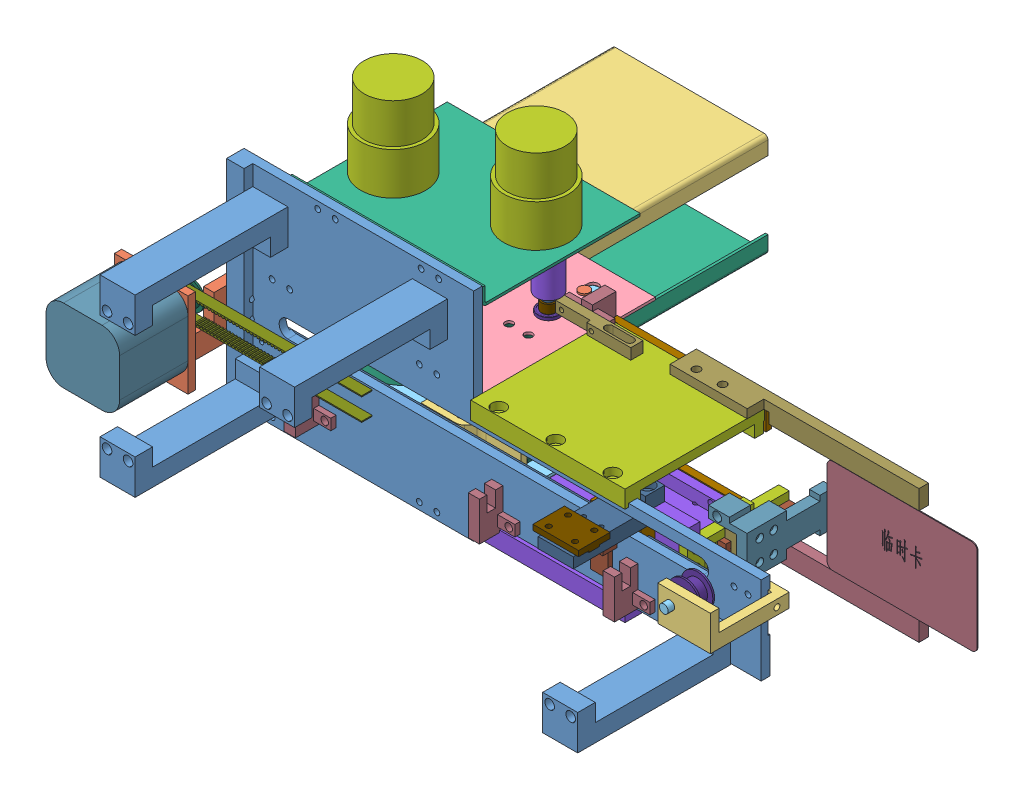
SolidWorks assembly 存储卡, configuration 默认. Lengths in mm.
Overall size (373.35 177.6 304.15).
71 component instances, 51 part files, 165 mates.
Components (placement in the parent):
- C017-1: C017 [默认] at (-172.2765 -67.8832 295) size (300 123.7 10)
- C003-1: C003 [默认] at (-172.9765 -8.6832 223) size (86 56 10)
- C004-1: C004 [默认] at (-85.4265 45.8168 83) x (-1 0 0) z (0 0 1) size (89.1 18.5 152)
- C005-2: C005 [默认] at (-37.6765 45.8168 295) x (0 -1 0) z (-1 0 0) size (10 100 134.6)
- 镜向C005-3: 镜向C005 [默认] at (-37.6765 -10.1832 295) x (0 1 0) z (1 0 0) size (10 100 134.6)
- C001-2: C001 [默认] at (-174.5265 -10.1832 83) size (89.1 33.5 152)
- C006-1-1: C006-1 [默认] at (68.7235 9.8168 231) x (0 1 0) z (1 0 0) size (24 57 6)
- C006-2-1: C006-2 [默认] at (73.7235 35.0668 291) x (0 -1 0) z (0 0 -1) size (34.5 50 13)
- MGN9C滑块-1: MGN9C滑块 [默认] at (24.2735 27.8168 286) x (0 -1 0) z (0 0 1) size (20 28.9 8)
- MGN9C线轨-265-1: MGN9C线轨-265 [默认] at (100.2235 13.3168 289.5) x (0 1 0) z (0 0 1) size (9 265 6.5)
- MGN7C线轨-40-1: MGN7C线轨-40 [默认] at (73.7235 14.3168 231) x (0 1 0) z (1 0 0) size (7 40 4.8)
- MGN7C滑块-1: MGN7C滑块 [默认] at (81.7235 9.3168 245.55) x (0 0 1) z (-1 0 0) size (22.5 17 6.5)
- 临时身份证卡片-1: 临时身份证卡片 [默认] at (88.3058 -9.1832 222.5) size (85.6 54 0.5)
- C007-1: C007 [默认] at (87.7235 17.8168 268.1) x (1 0 0) z (0 0 -1) size (22 30 49.6)
- C011-1: C011 [默认] at (-60.6765 -8.3832 224.8336) x (0 0 -1) z (0 -1 0) size (31.07 22 1.8)
- C012-1: C012 [默认] at (-60.6765 -9.3832 232.9) x (0.511883 0 -0.859055) z (0 1 0) size (8 8 1.2)
- MFL126ZZ-1: MFL126ZZ [默认] at (-60.6765 -13.3832 232.9) x (0 1 0) z (0.353832 0 -0.935309) size (23.7 35.7 35.7)
- C012-2: C012 [默认] at (-60.6765 45.0168 232.9) x (0.041323 0 -0.999146) z (0 -1 0) size (8 8 1.2)
- MFL126ZZ-2: MFL126ZZ [默认] at (-60.6765 49.0168 232.9) x (0 -1 0) z (-0.254645 0 -0.967035) size (23.7 35.7 35.7)
- C011-2: C011 [默认] at (-60.6765 44.0168 224.8336) x (0 0 -1) z (0 1 0) size (31.07 22 1.8)
- C015-1: C015 [默认] at (-60.6765 49.0168 232.9) x (-0.500335 0 -0.865832) z (0 1 0) size (8 8 5)
- C015-2: C015 [默认] at (-60.6765 -13.3832 232.9) x (0.575313 0 -0.817933) z (0 -1 0) size (8 8 5)
- 米思米止动扣环5-1: 米思米止动扣环5 [默认] at (-127.2765 -12.7832 247.9) x (-0.338524 0 -0.940958) z (0 1 0) size (11 8.93 0.6)
- MFL126ZZ-3: MFL126ZZ [默认] at (-127.2765 -8.4832 247.9) x (0 -1 0) z (0.834073 0 -0.551654) size (23.7 35.7 35.7)
- MFL126ZZ-4: MFL126ZZ [默认] at (-127.2765 44.1168 247.9) x (0 1 0) z (-0.070925 0 0.997482) size (23.7 35.7 35.7)
- 米思米止动扣环5-2: 米思米止动扣环5 [默认] at (-127.2765 48.4168 247.9) x (0.376434 0 -0.926444) z (0 1 0) size (11 8.93 0.6)
- C025-1: C025 [默认] at (-60.6765 45.3168 212.5) x (-0.469568 0 -0.882896) z (0 -1 0) size (8 8 61)
- C018-2: C018 [默认] at (-7934.5924 -10.1832 311.2708) x (1 0 0) z (0 1 0) size (50.64 10 10)
- 凸轮随动器-1: 凸轮随动器 [默认] at (84.7235 2.0168 265.1) x (0.072008 0 0.997404) z (0 -1 0) size (10 10 17.3)
- 米思米包胶滚轮ROUAKN20-8-15 -1: 米思米包胶滚轮ROUAKN20-8-15  [默认] at (-60.6765 43.8168 232.9) x (0.516691 0 -0.856172) z (0 -1 0) size (20 20 15)
- 米思米包胶滚轮ROUAKN20-8-15 -2: 米思米包胶滚轮ROUAKN20-8-15  [默认] at (-60.6765 28.8168 212.5) x (0.550183 0 0.835044) z (0 1 0) size (20 20 15)
- 米思米包胶滚轮ROUAKN20-8-15 -3: 米思米包胶滚轮ROUAKN20-8-15  [默认] at (-60.6765 6.8168 232.9) x (0.772118 0 -0.63548) z (0 -1 0) size (20 20 15)
- 米思米包胶滚轮ROUAKN20-8-15 -4: 米思米包胶滚轮ROUAKN20-8-15  [默认] at (-60.6765 -8.1832 212.5) x (0.999916 0 -0.01299) z (0 1 0) size (20 20 15)
- 米思米包胶滚轮ROUAKN50-12-30-1: 米思米包胶滚轮ROUAKN50-12-30 [默认] at (-127.2765 32.9168 247.9) x (0.950916 0 0.309448) z (0 -1 0) size (50 50 30)
- C019-1: C019 [默认] at (-35.9765 50.8168 302) x (0 0 1) z (1 0 0) size (79.6 12 88)
- 镜向C019-2: 镜向C019 [默认] at (-35.9765 -15.1832 302) x (0 0 1) z (-1 0 0) size (79.6 12 88)
- C020-1: C020 [默认] at (52.0235 38.8168 218.4) x (0 -1 0) z (0 0 1) size (12 88 4)
- C020-2: C020 [默认] at (-35.9765 -3.1832 218.4) x (0 1 0) z (0 0 1) size (12 88 4)
- C022-1: C022 [默认] at (53.7235 34.0668 281.04) x (0 -1 0) z (-1 0 0) size (15.25 52.16 20)
- C024-1: C024 [默认] at (53.7235 25.8168 308.3) x (-1 0 0) z (0 1 0) size (20 10.5 20)
- C026-1: C026 [默认] at (-54.9765 50.8168 234.7) x (1 0 0) z (0 1 0) size (45 7 6.2)
- EE-SX672遮光感应器-1: EE-SX672遮光感应器 [默认] at (-45.1765 60.2168 216.3) x (0 0 1) z (1 0 0) size (13.4 22.2 26)
- EE-SX672遮光感应器-2: EE-SX672遮光感应器 [默认] at (-130.9765 -6.4832 313.4) x (0 0 -1) z (1 0 0) size (13.4 22.2 26)
- EE-SX672遮光感应器-3: EE-SX672遮光感应器 [默认] at (-25.9765 -6.4832 313.4) x (0 0 -1) z (1 0 0) size (13.4 22.2 26)
- EE-SX672遮光感应器-4: EE-SX672遮光感应器 [默认] at (51.0235 -6.4832 313.4) x (0 0 -1) z (1 0 0) size (13.4 22.2 26)
- 42微型步进电机-1: 42微型步进电机 [默认] at (-199.4465 19.4168 380.8) x (0 1 0) z (0 0 -1) size (42 42 64)
- S2带轮-1: S2带轮 [默认] at (-178.4465 40.4168 318.8) x (-0.999895 -0.014472 0) z (0 0 1) size (16 16 16)
- S2M同步带-1: S2M同步带 [默认] at (-72.9684 34.4168 327.2) x (0 0 -1) z (-1 0 0) size (6 13.2 112.08)
- S2惰轮-1: S2惰轮 [默认] at (111.8256 40.4168 319.7) x (-0.381526 0.924358 0) z (0 0 1) size (18 18 8.5)
- S2M金属件-1: S2M金属件 [默认] at (30.7235 38.4168 315.2) x (1 0 0) z (0 -1 0) size (26 18 4)
- C023-4: C023 [默认] at (110.2235 -7.8832 300) x (0 -1 0) z (-1 0 0) size (20 87.15 20)
- C027-1: C027 [默认] at (-172.2765 40.8168 295.9995) x (0 -1 0) z (-1 0 0) size (48.6 50.8 42)
- C028-1: C028 [默认] at (124.7235 35.8168 311) x (0 -1 0) z (1 0 0) size (20 45 30)
- C029-1: C029 [默认] at (111.8256 40.4168 328.2) x (0.638272 -0.769811 0) z (0 0 1) size (7 7 2.8)
- 轴承止动销-1: 轴承止动销 [默认] at (111.8256 40.4168 317.7) x (0.999959 0.009096 0) z (0 0 1) size (8 8 22)
- C016-2: C016 [默认] at (-36.2765 92.9168 295) x (0 1 0) z (-1 0 0) size (10 90 110.1)
- 金顺来JGB37-520电机-12-66-3: 金顺来JGB37-520电机-12-66 [默认] at (-127.2765 94.4168 254.9) x (1 0 0) z (0 1 0) size (37 37 68.2)
- 金顺来JGB37-520电机-12-66-4: 金顺来JGB37-520电机-12-66 [默认] at (-60.6765 94.4168 239.9) x (1 0 0) z (0 1 0) size (37 37 68.2)
- LM-14联轴器-3: LM-14联轴器 [默认] at (-60.6765 79.9168 232.9) x (-0.273099 0 -0.961986) z (0 -1 0) size (14 14 22)
- LM-14联轴器-4: LM-14联轴器 [默认] at (-127.2765 79.9168 247.9) x (0.762245 0 -0.647289) z (0 -1 0) size (14 14 22)
- C014-2: C014 [默认] at (-60.6765 -18.1832 232.9) x (0.10754 0 0.994201) z (0 1 0) size (9 9 26)
- C010-2: C010 [默认] at (-60.6765 63.8168 232.9) x (0.999999 0 0.001231) z (0 -1 0) size (9 9 36)
- C009-3: C009 [默认] at (-127.2765 2.9168 247.9) x (0.688202 0 0.725519) z (0 1 0) size (12 12 80)
- C023-6: C023 [默认] at (-142.2765 -7.8832 300) x (0 -1 0) z (-1 0 0) size (20 87.15 20)
- C023-10: C023 [默认] at (-162.2765 92.1168 300) x (0 1 0) z (1 0 0) size (20 87.15 20)
- C023-11: C023 [默认] at (-71.2765 92.1168 300) x (0 1 0) z (1 0 0) size (20 87.15 20)
- C030-1: C030 [默认] at (8.1653 55.8168 222.4) x (1 0 0) z (0 -1 0) size (132.46 15 10.95)
- 镜向C030-2: 镜向C030 [默认] at (8.1653 -20.1832 222.4) x (1 0 0) z (0 -1 0) size (132.46 15 10.95)
- EE-SX672遮光感应器-5: EE-SX672遮光感应器 [默认] at (-140.8265 -36.4832 197.2) x (-1 0 0) z (0 0 -1) size (13.4 22.2 26)
- 弹簧1-1: 弹簧1 [默认] at (-145.1696 -18.7662 204.6463) x (-0.417818 -0.908531 0) z (0.908531 -0.417818 0) size (22.1 22.42 1.18)
- C031-1: C031 [默认] at (-147.0265 -0.6832 202) x (0 0 -1) z (-1 0 0) size (17 16 2)
Mates (geometry in assembly coordinates):
- 重合1: coincident aligned: plane of C017-1 through (-172.2765 -67.8832 305) normal (-1 0 0); plane of C005-2 through (-172.2765 55.8168 295) normal (-1 0 0)
- 重合3: coincident anti-aligned: plane of C017-1 through (-172.2765 -67.8832 295) normal (0 0 -1); plane of C005-2 through (-37.6765 45.8168 295) normal (0 0 1)
- 同心1: concentric anti-aligned: cylinder of C004-1 through (-165.9765 51.8168 225) axis (0 0 1) radius 2.25; cylinder of C005-2 through (-165.9765 51.8168 245) axis (0 0 -1) radius 2.25
- 同心2: concentric anti-aligned: cylinder of C004-1 through (-93.9765 51.8168 225) axis (0 0 1) radius 2.25; cylinder of C005-2 through (-93.9765 51.8168 245) axis (0 0 -1) radius 2.25
- 重合4: coincident anti-aligned: plane of C004-1 through (-85.4265 45.8168 235) normal (0 0 1); plane of C005-2 through (-37.6765 45.8168 235) normal (0 0 -1)
- 同心3: concentric anti-aligned: cylinder of 镜向C005-3 through (-165.9765 -16.1832 245) axis (0 0 -1) radius 2.25; cylinder of C001-2 through (-165.9765 -16.1832 225) axis (0 0 1) radius 2.25
- 同心4: concentric anti-aligned: cylinder of 镜向C005-3 through (-93.9765 -16.1832 245) axis (0 0 -1) radius 2.25; cylinder of C001-2 through (-93.9765 -16.1832 225) axis (0 0 1) radius 2.25
- 重合5: coincident anti-aligned: plane of 镜向C005-3 through (-37.6765 -10.1832 235) normal (0 0 -1); plane of C001-2 through (-174.5265 -10.1832 235) normal (0 0 1)
- 同心5: concentric aligned: circle of C003-1; cylinder of C004-1 through (-102.4765 37.3168 228.5) axis (0 1 0) radius 2.25
- 同心6: concentric aligned: cylinder of C003-1 through (-157.4765 -10.1832 228.5) axis (0 1 0) radius 2.0729; cylinder of C004-1 through (-157.4765 37.3168 228.5) axis (0 1 0) radius 2.25
- 重合6: coincident anti-aligned: plane of C003-1 through (-172.9765 45.8168 223) normal (0 1 0); plane of C004-1 through (-85.4265 45.8168 235) normal (0 -1 0)
- 同心9: concentric aligned: cylinder of C006-1-1 through (68.7235 22.5668 283) axis (1 0 0) radius 2.25; cylinder of C006-2-1 through (68.7235 22.5668 283) axis (1 0 0) radius 1.65
- 同心10: concentric aligned: cylinder of C006-1-1 through (68.7235 13.0668 283) axis (1 0 0) radius 2.25; cylinder of C006-2-1 through (68.7235 13.0668 283) axis (1 0 0) radius 1.65
- 重合8: coincident anti-aligned: plane of C006-1-1 through (68.7235 9.8168 231) normal (-1 0 0); plane of C006-2-1 through (68.7235 25.8168 291) normal (1 0 0)
- 同心11: concentric anti-aligned: cylinder of C017-1 through (-157.2765 17.8168 300) axis (0 0 1) radius 1.25; cylinder of MGN9C线轨-265-1 through (-157.2765 17.8168 289.5) axis (0 0 -1) radius 3.25
- 同心12: concentric anti-aligned: cylinder of C017-1 through (92.7235 17.8168 300) axis (0 0 1) radius 1.25; cylinder of MGN9C线轨-265-1 through (92.7235 17.8168 289.5) axis (0 0 -1) radius 3.25
- 重合9: coincident anti-aligned: plane of C017-1 through (-172.2765 22.3168 296) normal (0 0 -1); plane of MGN9C线轨-265-1 through (100.2235 13.3168 296) normal (0 0 1)
- 同心13: concentric aligned: cylinder of C006-2-1 through (33.7235 10.3168 281) axis (0 0 -1) radius 3.25; cylinder of MGN9C滑块-1 through (33.7235 10.3168 286) axis (0 0 -1) radius 1.25
- 同心14: concentric aligned: cylinder of C006-2-1 through (33.7235 25.3168 281) axis (0 0 -1) radius 3.25; cylinder of MGN9C滑块-1 through (33.7235 25.3168 286) axis (0 0 -1) radius 1.25
- 重合10: coincident anti-aligned: plane of C006-2-1 through (73.7235 27.8168 286) normal (0 0 1); plane of MGN9C滑块-1 through (24.2735 27.8168 286) normal (0 0 -1)
- 重合11: coincident anti-aligned: plane of MGN9C滑块-1 through (24.2735 13.3168 294) normal (0 1 0); plane of MGN9C线轨-265-1 through (100.2235 13.3168 296) normal (0 -1 0)
- 重合12: coincident anti-aligned: plane of MGN9C滑块-1 through (24.2735 22.3168 289.5) normal (0 0 1); plane of MGN9C线轨-265-1 through (100.2235 13.3168 289.5) normal (0 0 -1)
- 同心15: concentric anti-aligned: cylinder of C006-1-1 through (68.7235 17.8168 236) axis (-1 0 0) radius 1.25; cylinder of MGN7C线轨-40-1 through (78.5235 17.8168 236) axis (1 0 0) radius 2.2
- 同心16: concentric anti-aligned: cylinder of C006-1-1 through (68.7235 17.8168 266) axis (-1 0 0) radius 1.25; circle of MGN7C线轨-40-1
- 重合13: coincident anti-aligned: plane of C006-1-1 through (73.7235 9.8168 231) normal (1 0 0); plane of MGN7C线轨-40-1 through (73.7235 14.3168 231) normal (-1 0 0)
- 重合14: coincident anti-aligned: plane of MGN7C线轨-40-1 through (78.5235 14.3168 231) normal (0 -1 0); plane of MGN7C滑块-1 through (75.2235 14.3168 268.05) normal (0 1 0)
- 重合15: coincident anti-aligned: plane of MGN7C线轨-40-1 through (78.5235 14.3168 231) normal (1 0 0); plane of MGN7C滑块-1 through (78.5235 14.3168 268.05) normal (-1 0 0)
- 对称1: symmetric aligned: plane of 临时身份证卡片-1 through (88.3058 44.8168 223) normal (0 1 0); plane of 临时身份证卡片-1 through (88.3058 -9.1832 223) normal (0 -1 0); plane of assembly through (0 17.8168 0) normal (0 -1 0)
- 重合16: coincident anti-aligned: plane of C003-1 through (-172.9765 -8.6832 223) normal (0 0 -1); plane of 临时身份证卡片-1 through (88.3058 -9.1832 223) normal (0 0 1)
- 同心17: concentric aligned: cylinder of MGN7C滑块-1 through (81.7235 23.8168 252.8) axis (1 0 0) radius 0.8; cylinder of C007-1 through (87.7235 23.8168 252.8) axis (1 0 0) radius 2.2
- 同心18: concentric aligned: cylinder of MGN7C滑块-1 through (81.7235 23.8168 260.8) axis (1 0 0) radius 0.8; cylinder of C007-1 through (87.7235 23.8168 260.8) axis (1 0 0) radius 2.2
- 重合17: coincident anti-aligned: plane of MGN7C滑块-1 through (81.7235 9.3168 245.55) normal (1 0 0); plane of C007-1 through (81.7235 9.3168 218.5) normal (-1 0 0)
- 同心24: concentric anti-aligned: cylinder of 镜向C005-3 through (-60.6765 -1.6832 232.9) axis (0 -1 0) radius 6; cylinder of MFL126ZZ-1 through (-60.6765 -13.2332 232.9) axis (0 1 0) radius 3
- 重合21: coincident anti-aligned: plane of 镜向C005-3 through (-172.2765 -10.1832 295) normal (0 1 0); plane of MFL126ZZ-1 through (-69.5479 -10.1832 236.9015) normal (0 -1 0)
- 重合22: coincident anti-aligned: plane of C011-1 through (-60.6765 -9.3832 232.9) normal (0 -1 0); plane of MFL126ZZ-1 through (-64.678 -9.3832 224.0286) normal (0 1 0)
- 平行1: parallel aligned: plane of 镜向C005-3 through (-37.6765 -10.1832 295) normal (1 0 0); plane of C011-1 through (-49.6765 -10.1832 232.9) normal (1 0 0)
- 重合24: coincident anti-aligned: plane of C012-1 through (-60.6765 -9.3832 232.9) normal (0 -1 0); plane of MFL126ZZ-1 through (-62.9509 -9.3832 227.8577) normal (0 1 0)
- 同心28: concentric aligned: cylinder of C005-2 through (-60.6765 37.3168 232.9) axis (0 1 0) radius 6; cylinder of C012-2 through (-60.6765 43.8168 232.9) axis (0 1 0) radius 4
- 重合27: coincident anti-aligned: plane of C005-2 through (-172.2765 45.8168 295) normal (0 -1 0); plane of MFL126ZZ-2 through (-52.2694 45.8168 237.8024) normal (0 1 0)
- 重合28: coincident anti-aligned: plane of C012-2 through (-60.6765 45.0168 232.9) normal (0 1 0); plane of MFL126ZZ-2 through (-57.8901 45.0168 228.1215) normal (0 -1 0)
- 重合29: coincident anti-aligned: plane of MFL126ZZ-2 through (-55.7741 45.0168 224.4929) normal (0 -1 0); plane of C011-2 through (-60.6765 45.0168 232.9) normal (0 1 0)
- 平行2: parallel aligned: plane of C005-2 through (-37.6765 45.8168 295) normal (1 0 0); plane of C011-2 through (-49.6765 45.8168 255.9) normal (1 0 0)
- 重合32: coincident anti-aligned: plane of MFL126ZZ-2 through (-55.8981 49.0168 235.6864) normal (0 1 0); plane of C015-1 through (-60.6765 49.0168 232.9) normal (0 -1 0)
- 重合33: coincident anti-aligned: plane of MFL126ZZ-1 through (-65.7188 -13.3832 235.1744) normal (0 -1 0); plane of C015-2 through (-60.6765 -13.3832 232.9) normal (0 1 0)
- 重合40: coincident anti-aligned: plane of 镜向C005-3 through (-172.2765 -11.6832 295) normal (0 -1 0); plane of MFL126ZZ-3 through (-129.22 -11.6832 257.436) normal (0 1 0)
- 重合42: coincident anti-aligned: plane of C005-2 through (-172.2765 47.3168 295) normal (0 1 0); plane of MFL126ZZ-4 through (-119.9242 47.3168 241.5238) normal (0 -1 0)
- 重合45: coincident anti-aligned: plane of 米思米止动扣环5-1 through (-122.1148 -12.4832 251.9583) normal (0 1 0); plane of MFL126ZZ-3 through (-121.8564 -12.4832 249.0046) normal (0 -1 0)
- 重合46: coincident anti-aligned: plane of MFL126ZZ-4 through (-123.6524 48.1168 252.0789) normal (0 1 0); plane of 米思米止动扣环5-2 through (-121.9544 48.1168 244.0546) normal (0 -1 0)
- 同心40: concentric anti-aligned: cylinder of C005-2 through (-60.6765 37.3168 212.5) axis (0 1 0) radius 3; cylinder of C025-1 through (-60.6765 48.3168 212.5) axis (0 -1 0) radius 3
- 对称3: symmetric aligned: plane of C025-1 through (-60.6765 -9.6832 212.5) normal (0 -1 0); plane of C025-1 through (-60.6765 45.3168 212.5) normal (0 1 0); plane of assembly through (0 17.8168 0) normal (0 -1 0)
- 同心43: concentric anti-aligned: cylinder of 镜向C005-3 through (-81.8765 -1.6832 261.6) axis (0 -1 0) radius 2.25; cylinder of C018-2 through (-81.8765 -0.1832 261.6) axis (0 1 0) radius 1.65
- 同心44: concentric anti-aligned: cylinder of 镜向C005-3 through (-93.8765 -1.6832 261.6) axis (0 -1 0) radius 2.25; cylinder of C018-2 through (-93.8765 -0.1832 261.6) axis (0 1 0) radius 1.65
- 重合48: coincident anti-aligned: plane of 镜向C005-3 through (-172.2765 -10.1832 295) normal (0 1 0); plane of C018-2 through (-7934.5924 -10.1832 311.2708) normal (0 -1 0)
- 同心45: concentric aligned: cylinder of C007-1 through (84.7235 5.8168 265.1) axis (0 -1 0) radius 1.25; cylinder of 凸轮随动器-1 through (84.7235 10.3168 265.1) axis (0 -1 0) radius 1.5
- 距离1: distance = 4.5 mm anti-aligned: plane of 凸轮随动器-1 through (84.7235 10.3168 265.1) normal (0 1 0); plane of C007-1 through (77.7235 5.8168 218.5) normal (0 -1 0)
- LimitDistance1: limit distance = 0 mm anti-aligned: plane of C007-1 through (65.7235 2.8168 256.1) normal (0 0 -1); plane of C006-1-1 through (74.7235 25.8168 256.1) normal (0 0 1)
- 同心47: concentric anti-aligned: cylinder of C025-1 through (-60.6765 -9.6832 212.5) axis (0 1 0) radius 4; cylinder of 米思米包胶滚轮ROUAKN20-8-15 -2 through (-60.6765 43.8168 212.5) axis (0 -1 0) radius 4
- 重合50: coincident aligned: plane of 米思米包胶滚轮ROUAKN20-8-15 -1 through (-60.6765 28.8168 232.9) normal (0 -1 0); plane of 米思米包胶滚轮ROUAKN20-8-15 -2 through (-60.6765 28.8168 212.5) normal (0 -1 0)
- 同心50: concentric anti-aligned: cylinder of C025-1 through (-60.6765 -9.6832 212.5) axis (0 1 0) radius 4; cylinder of 米思米包胶滚轮ROUAKN20-8-15 -4 through (-60.6765 6.8168 212.5) axis (0 -1 0) radius 4
- 重合53: coincident aligned: plane of 米思米包胶滚轮ROUAKN20-8-15 -3 through (-60.6765 6.8168 232.9) normal (0 1 0); plane of 米思米包胶滚轮ROUAKN20-8-15 -4 through (-60.6765 6.8168 212.5) normal (0 1 0)
- 同心52: concentric aligned: cylinder of C017-1 through (40.5235 42.8168 297.5) axis (0 1 0) radius 1.65; cylinder of C019-1 through (40.5235 50.8168 297.5) axis (0 1 0) radius 4
- 同心56: concentric aligned: cylinder of C017-1 through (8.0235 42.8168 297.5) axis (0 1 0) radius 1.65; cylinder of C019-1 through (8.0235 50.8168 297.5) axis (0 1 0) radius 4
- 重合55: coincident anti-aligned: plane of C017-1 through (-36.2765 42.8168 305) normal (0 1 0); plane of C019-1 through (52.0235 42.8168 295) normal (0 -1 0)
- 同心57: concentric aligned: cylinder of C019-1 through (40.5235 47.8168 222.4) axis (0 0 -1) radius 1.25; cylinder of C020-1 through (40.5235 47.8168 222.4) axis (0 0 -1) radius 1.75
- 同心58: concentric aligned: cylinder of C019-1 through (8.0235 47.8168 222.4) axis (0 0 -1) radius 1.25; cylinder of C020-1 through (8.0235 47.8168 222.4) axis (0 0 -1) radius 1.75
- 重合56: coincident anti-aligned: plane of C019-1 through (52.0235 50.8168 222.4) normal (0 0 -1); plane of C020-1 through (52.0235 38.8168 222.4) normal (0 0 1)
- 同心59: concentric aligned: cylinder of 镜向C019-2 through (40.5235 -12.1832 222.4) axis (0 0 -1) radius 1.25; cylinder of C020-2 through (40.5235 -12.1832 222.4) axis (0 0 -1) radius 1.75
- 同心60: concentric aligned: cylinder of 镜向C019-2 through (8.0235 -12.1832 222.4) axis (0 0 -1) radius 1.25; cylinder of C020-2 through (8.0235 -12.1832 222.4) axis (0 0 -1) radius 1.75
- 重合57: coincident anti-aligned: plane of 镜向C019-2 through (52.0235 -15.1832 222.4) normal (0 0 -1); plane of C020-2 through (-35.9765 -3.1832 222.4) normal (0 0 1)
- 同心61: concentric aligned: cylinder of C006-2-1 through (38.7235 34.0668 286) axis (0 1 0) radius 1.65; cylinder of C022-1 through (38.7235 43.0668 286) axis (0 1 0) radius 4
- 同心62: concentric aligned: cylinder of C006-2-1 through (48.7235 34.0668 286) axis (0 1 0) radius 1.65; cylinder of C022-1 through (48.7235 43.0668 286) axis (0 1 0) radius 4
- 重合58: coincident anti-aligned: plane of C006-2-1 through (73.7235 34.0668 291) normal (0 1 0); plane of C022-1 through (33.7235 34.0668 291.04) normal (0 -1 0)
- 同心63: concentric aligned: cylinder of C022-1 through (48.7235 27.8168 312.3) axis (0 -1 0) radius 1.25; cylinder of C024-1 through (48.7235 45.8168 312.3) axis (0 -1 0) radius 1.75
- 同心64: concentric aligned: cylinder of C022-1 through (38.7235 27.8168 312.3) axis (0 -1 0) radius 1.25; cylinder of C024-1 through (38.7235 45.8168 312.3) axis (0 -1 0) radius 1.75
- 重合59: coincident anti-aligned: plane of C022-1 through (33.7235 27.8168 291.04) normal (0 -1 0); plane of C024-1 through (53.7235 27.8168 308.3) normal (0 1 0)
- 同心67: concentric anti-aligned: cylinder of C017-1 through (95.2235 7.1168 295) axis (0 0 1) radius 2.25; cylinder of C023-4 through (95.2235 7.1168 300) axis (0 0 -1) radius 1.65
- 同心68: concentric anti-aligned: cylinder of C017-1 through (105.2235 7.1168 295) axis (0 0 1) radius 2.25; cylinder of C023-4 through (105.2235 7.1168 300) axis (0 0 -1) radius 1.65
- 重合61: coincident anti-aligned: plane of C017-1 through (-172.2765 -67.8832 300) normal (0 0 1); plane of C023-4 through (90.2235 12.1168 300) normal (0 0 -1)
- 重合62: coincident anti-aligned: plane of C019-1 through (52.0235 50.8168 302) normal (0 1 0); plane of C026-1 through (-54.9765 50.8168 234.7) normal (0 -1 0)
- 平行3: parallel aligned: plane of C005-2 through (-37.6765 45.8168 295) normal (1 0 0); plane of C026-1 through (-9.9765 57.0168 236.7) normal (1 0 0)
- 同心69: concentric anti-aligned: cylinder of C026-1 through (-32.4765 53.9168 236.7) axis (0 0 1) radius 1.25; cylinder of EE-SX672遮光感应器-1 through (-32.4765 53.9168 236.5) axis (0 0 -1) radius 2.15
- 同心70: concentric anti-aligned: cylinder of C026-1 through (-51.4765 53.9168 236.7) axis (0 0 1) radius 1.25; cylinder of EE-SX672遮光感应器-1 through (-51.4765 53.9168 236.5) axis (0 0 -1) radius 2.15
- 重合64: coincident anti-aligned: plane of C026-1 through (-9.9765 57.0168 229.7) normal (0 0 -1); plane of EE-SX672遮光感应器-1 through (-38.7765 60.2168 229.7) normal (0 0 1)
- 同心71: concentric anti-aligned: cylinder of C019-1 through (-13.9765 50.8168 233.2) axis (0 1 0) radius 1.65; cylinder of C026-1 through (-13.9765 57.0168 233.2) axis (0 -1 0) radius 2.25
- 同心72: concentric aligned: cylinder of C017-1 through (-118.2765 -0.1832 300) axis (0 0 1) radius 1.25; cylinder of EE-SX672遮光感应器-2 through (-118.2765 -0.1832 293.2) axis (0 0 1) radius 2.15
- 同心73: concentric aligned: cylinder of C017-1 through (-137.2765 -0.1832 300) axis (0 0 1) radius 1.25; cylinder of EE-SX672遮光感应器-2 through (-137.2765 -0.1832 293.2) axis (0 0 1) radius 2.15
- 重合65: coincident anti-aligned: plane of C017-1 through (-172.2765 -67.8832 300) normal (0 0 1); plane of EE-SX672遮光感应器-2 through (-124.5765 -6.4832 300) normal (0 0 -1)
- 同心81: concentric aligned: cylinder of C022-1 through (36.2235 27.8168 318.7) axis (0 -1 0) radius 1.25; cylinder of S2M金属件-1 through (36.2235 39.3168 318.7) axis (0 -1 0) radius 1.5
- 同心82: concentric aligned: cylinder of C022-1 through (36.2235 27.8168 329.7) axis (0 -1 0) radius 1.25; cylinder of S2M金属件-1 through (36.2235 39.3168 329.7) axis (0 -1 0) radius 1.5
- 重合72: coincident anti-aligned: plane of C022-1 through (33.7235 33.8168 315.2) normal (0 1 0); plane of S2M同步带-1 through (-172.9684 33.8168 327.2) normal (0 -1 0)
- 重合73: coincident aligned: plane of S2M同步带-1 through (-172.9684 34.4168 321.2) normal (0 0 -1); plane of S2M金属件-1 through (30.7235 34.4168 321.2) normal (0 0 -1)
- 重合74: coincident anti-aligned: plane of S2M同步带-1 through (-172.9684 34.4168 327.2) normal (0 1 0); plane of S2M金属件-1 through (30.7235 34.4168 315.2) normal (0 -1 0)
- 同心83: concentric anti-aligned: cylinder of 42微型步进电机-1 through (-178.4465 40.4168 316.8) axis (0 0 1) radius 2.5; cylinder of S2带轮-1 through (-178.4465 40.4168 334.8) axis (0 0 -1) radius 2.5
- 重合75: coincident anti-aligned: plane of S2带轮-1 through (-178.4465 40.4168 327.2) normal (0 0 -1); plane of S2M同步带-1 through (-172.9684 34.4168 327.2) normal (0 0 1)
- 同心85: concentric aligned: cylinder of S2带轮-1 through (-178.4465 40.4168 327.2) axis (0 0 -1) radius 6; cylinder of S2M同步带-1 through (-178.4465 40.4168 327.2) axis (0 0 -1) radius 6
- 距离3: distance = 2 mm aligned: plane of 42微型步进电机-1 through (-178.4465 40.4168 316.8) normal (0 0 -1); plane of S2带轮-1 through (-178.4465 40.4168 318.8) normal (0 0 -1)
- 平行8: parallel aligned: plane of C017-1 through (-172.2765 -67.8832 305) normal (-1 0 0); plane of 42微型步进电机-1 through (-199.4465 19.4168 341.8) normal (-1 0 0)
- 重合78: coincident aligned: plane of S2带轮-1 through (-178.4465 40.4168 327.2) normal (0 0 -1); plane of S2惰轮-1 through (111.8256 40.4168 327.2) normal (0 0 -1)
- 相切1: tangent anti-aligned: plane of S2M同步带-1 through (-172.9684 34.4168 327.2) normal (0 1 0); cylinder of S2惰轮-1 through (111.8256 40.4168 327.2) axis (0 0 -1) radius 6
- 同心86: concentric aligned: cylinder of C017-1 through (-172.2765 36.8168 300.304) axis (-1 0 0) radius 1.65; cylinder of C027-1 through (-172.2765 36.8168 300.304) axis (-1 0 0) radius 2.1
- 同心87: concentric aligned: cylinder of C017-1 through (-172.2765 26.8168 300.304) axis (-1 0 0) radius 1.65; cylinder of C027-1 through (-172.2765 26.8168 300.304) axis (-1 0 0) radius 2.1
- 重合79: coincident anti-aligned: plane of C017-1 through (-172.2765 -67.8832 305) normal (-1 0 0); plane of C027-1 through (-172.2765 40.8168 295.9995) normal (1 0 0)
- 重合80: coincident anti-aligned: plane of C017-1 through (-172.2765 35.8168 295) normal (0 -1 0); plane of C028-1 through (134.7235 35.8168 311) normal (0 1 0)
- 重合81: coincident anti-aligned: plane of C017-1 through (-172.2765 35.8168 296) normal (0 0 -1); plane of C028-1 through (129.7235 25.8168 296) normal (0 0 1)
- 同心88: concentric aligned: cylinder of C028-1 through (111.8256 40.4168 336) axis (0 0 -1) radius 2.5; cylinder of C029-1 through (111.8256 40.4168 331) axis (0 0 -1) radius 2.5
- 重合82: coincident anti-aligned: plane of S2惰轮-1 through (111.8256 40.4168 328.2) normal (0 0 1); plane of C029-1 through (111.8256 40.4168 328.2) normal (0 0 -1)
- 同心89: concentric anti-aligned: cylinder of S2惰轮-1 through (111.8256 40.4168 319.7) axis (0 0 1) radius 2.5; cylinder of C029-1 through (111.8256 40.4168 331) axis (0 0 -1) radius 2.5
- 距离4: distance = 2 mm anti-aligned: plane of C017-1 through (127.7235 -7.1832 305) normal (1 0 0); plane of C028-1 through (129.7235 25.8168 311) normal (-1 0 0)
- 重合84: coincident aligned: plane of 42微型步进电机-1 through (-199.4465 19.4168 341.8) normal (-1 0 0); plane of C027-1 through (-199.4465 12.8168 337.5995) normal (-1 0 0)
- LimitDistance2: limit distance = 206 mm aligned: plane of C017-1 through (-172.2765 -67.8832 305) normal (-1 0 0); plane of C022-1 through (33.7235 34.0668 281.04) normal (-1 0 0)
- 同心93: concentric anti-aligned: cylinder of S2惰轮-1 through (111.8256 40.4168 319.7) axis (0 0 1) radius 2.5; cylinder of 轴承止动销-1 through (111.8256 40.4168 339.7) axis (0 0 -1) radius 2.5
- 重合85: coincident anti-aligned: plane of S2惰轮-1 through (111.8256 40.4168 319.7) normal (0 0 -1); plane of 轴承止动销-1 through (111.8256 40.4168 319.7) normal (0 0 1)
- 平行13: parallel aligned: plane of C017-1 through (-172.2765 -67.8832 305) normal (-1 0 0); plane of C016-2 through (-146.3765 92.9168 295) normal (-1 0 0)
- 重合90: coincident anti-aligned: plane of C017-1 through (-172.2765 -67.8832 295) normal (0 0 -1); plane of C016-2 through (-36.2765 92.9168 295) normal (0 0 1)
- 距离6: distance = 0.6 mm aligned: plane of C016-2 through (-146.3765 102.9168 295) normal (0 1 0); plane of C017-1 through (-172.2765 103.5168 295) normal (0 1 0)
- 重合94: coincident aligned: plane of C017-1 through (-172.2765 -20.1832 342.7) normal (0 -1 0); plane of 镜向C005-3 through (-37.6765 -20.1832 295) normal (0 -1 0)
- 同心98: concentric anti-aligned: cylinder of 米思米包胶滚轮ROUAKN20-8-15 -3 through (-60.6765 -8.1832 232.9) axis (0 1 0) radius 4; cylinder of C014-2 through (-60.6765 6.8168 232.9) axis (0 -1 0) radius 4
- 重合95: coincident anti-aligned: plane of 米思米包胶滚轮ROUAKN20-8-15 -3 through (-60.6765 6.8168 232.9) normal (0 1 0); plane of C014-2 through (-60.6765 6.8168 232.9) normal (0 -1 0)
- 同心100: concentric anti-aligned: cylinder of MFL126ZZ-1 through (-60.6765 -13.2332 232.9) axis (0 1 0) radius 3; cylinder of C014-2 through (-60.6765 -8.1832 232.9) axis (0 -1 0) radius 3
- 同心101: concentric aligned: cylinder of MFL126ZZ-1 through (-60.6765 -13.2332 232.9) axis (0 1 0) radius 3; cylinder of C015-2 through (-60.6765 -18.3832 232.9) axis (0 1 0) radius 3
- 重合96: coincident anti-aligned: plane of C012-1 through (-60.6765 -8.1832 232.9) normal (0 1 0); plane of C014-2 through (-60.6765 -8.1832 232.9) normal (0 -1 0)
- 同心102: concentric aligned: cylinder of 米思米包胶滚轮ROUAKN20-8-15 -1 through (-60.6765 28.8168 232.9) axis (0 1 0) radius 4; cylinder of C010-2 through (-60.6765 28.8168 232.9) axis (0 1 0) radius 4
- 同心103: concentric anti-aligned: cylinder of MFL126ZZ-2 through (-60.6765 48.8668 232.9) axis (0 -1 0) radius 3; cylinder of C010-2 through (-60.6765 28.8168 232.9) axis (0 1 0) radius 4
- 同心104: concentric aligned: cylinder of MFL126ZZ-2 through (-60.6765 48.8668 232.9) axis (0 -1 0) radius 3; cylinder of C015-1 through (-60.6765 54.0168 232.9) axis (0 -1 0) radius 3
- 重合98: coincident anti-aligned: plane of C012-2 through (-60.6765 43.8168 232.9) normal (0 -1 0); plane of C010-2 through (-60.6765 43.8168 232.9) normal (0 1 0)
- 同心105: concentric anti-aligned: cylinder of C005-2 through (-60.6765 37.3168 232.9) axis (0 1 0) radius 6; cylinder of MFL126ZZ-2 through (-60.6765 45.9668 232.9) axis (0 -1 0) radius 6
- 重合99: coincident anti-aligned: plane of 米思米包胶滚轮ROUAKN20-8-15 -1 through (-60.6765 28.8168 232.9) normal (0 -1 0); plane of C010-2 through (-60.6765 28.8168 232.9) normal (0 1 0)
- 同心106: concentric anti-aligned: cylinder of MFL126ZZ-4 through (-127.2765 44.2668 247.9) axis (0 1 0) radius 3; cylinder of C009-3 through (-127.2765 32.9168 247.9) axis (0 -1 0) radius 6
- 同心107: concentric aligned: cylinder of C005-2 through (-127.2765 37.3168 247.9) axis (0 1 0) radius 6; cylinder of MFL126ZZ-4 through (-127.2765 47.1668 247.9) axis (0 1 0) radius 6
- 重合100: coincident anti-aligned: plane of 米思米止动扣环5-1 through (-125.8833 -13.0832 241.4835) normal (0 -1 0); plane of C009-3 through (-127.2765 -13.0832 247.9) normal (0 1 0)
- 同心108: concentric anti-aligned: cylinder of 米思米包胶滚轮ROUAKN50-12-30-1 through (-127.2765 2.9168 247.9) axis (0 1 0) radius 6; cylinder of C009-3 through (-127.2765 32.9168 247.9) axis (0 -1 0) radius 6
- 重合101: coincident aligned: plane of 米思米包胶滚轮ROUAKN50-12-30-1 through (-127.2765 2.9168 247.9) normal (0 -1 0); plane of C009-3 through (-127.2765 2.9168 247.9) normal (0 -1 0)
- 同心109: concentric aligned: cylinder of LM-14联轴器-4 through (-127.2765 79.9168 247.9) axis (0 -1 0) radius 3; cylinder of C009-3 through (-127.2765 62.9168 247.9) axis (0 -1 0) radius 3
- 同心110: concentric anti-aligned: cylinder of C016-2 through (-127.2765 102.9168 247.9) axis (0 -1 0) radius 7; cylinder of 金顺来JGB37-520电机-12-66-3 through (-127.2765 88.4168 247.9) axis (0 1 0) radius 6
- 平行14: parallel aligned: plane of C017-1 through (-172.2765 -67.8832 295) normal (0 0 -1); plane of 金顺来JGB37-520电机-12-66-3 through (-124.5274 84.9168 245.4) normal (0 0 -1)
- 重合103: coincident aligned: plane of C017-1 through (-36.2765 55.8168 305) normal (1 0 0); plane of C016-2 through (-36.2765 102.9168 295) normal (1 0 0)
- 重合104: coincident anti-aligned: plane of C016-2 through (-146.3765 94.4168 295) normal (0 1 0); plane of 金顺来JGB37-520电机-12-66-3 through (-127.2765 94.4168 254.9) normal (0 -1 0)
- 距离7: distance = 13 mm anti-aligned: plane of LM-14联轴器-4 through (-127.2765 79.9168 247.9) normal (0 1 0); plane of C016-2 through (-146.3765 92.9168 295) normal (0 -1 0)
- 同心111: concentric anti-aligned: cylinder of LM-14联轴器-3 through (-60.6765 79.9168 232.9) axis (0 -1 0) radius 3; cylinder of C010-2 through (-60.6765 43.8168 232.9) axis (0 1 0) radius 3
- 同心112: concentric anti-aligned: cylinder of C016-2 through (-60.6765 102.9168 232.9) axis (0 -1 0) radius 7; cylinder of 金顺来JGB37-520电机-12-66-4 through (-60.6765 88.4168 232.9) axis (0 1 0) radius 6
- 平行15: parallel aligned: plane of C017-1 through (-172.2765 -67.8832 295) normal (0 0 -1); plane of 金顺来JGB37-520电机-12-66-4 through (-57.9274 84.9168 230.4) normal (0 0 -1)
- 重合107: coincident anti-aligned: plane of C016-2 through (-146.3765 94.4168 295) normal (0 1 0); plane of 金顺来JGB37-520电机-12-66-4 through (-60.6765 94.4168 239.9) normal (0 -1 0)
- 重合108: coincident aligned: plane of LM-14联轴器-3 through (-60.6765 79.9168 232.9) normal (0 1 0); plane of LM-14联轴器-4 through (-127.2765 79.9168 247.9) normal (0 1 0)
- 同心113: concentric anti-aligned: cylinder of C017-1 through (-147.2765 -2.8832 295) axis (0 0 1) radius 2.25; cylinder of C023-6 through (-147.2765 -2.8832 300) axis (0 0 -1) radius 1.65
- 同心114: concentric anti-aligned: cylinder of C017-1 through (-157.2765 -2.8832 295) axis (0 0 1) radius 2.25; cylinder of C023-6 through (-157.2765 -2.8832 300) axis (0 0 -1) radius 1.65
- 重合109: coincident anti-aligned: plane of C017-1 through (-172.2765 -67.8832 300) normal (0 0 1); plane of C023-6 through (-162.2765 12.1168 300) normal (0 0 -1)
- 同心125: concentric anti-aligned: cylinder of C017-1 through (-147.2765 77.1168 295) axis (0 0 1) radius 2.25; cylinder of C023-10 through (-147.2765 77.1168 300) axis (0 0 -1) radius 1.65
- 同心126: concentric anti-aligned: cylinder of C017-1 through (-157.2765 77.1168 295) axis (0 0 1) radius 2.25; cylinder of C023-10 through (-157.2765 77.1168 300) axis (0 0 -1) radius 1.65
- 重合117: coincident anti-aligned: plane of C017-1 through (-172.2765 -67.8832 300) normal (0 0 1); plane of C023-10 through (-142.2765 72.1168 300) normal (0 0 -1)
- 同心127: concentric aligned: cylinder of C017-1 through (-56.2765 87.1168 305) axis (0 0 -1) radius 2.25; cylinder of C023-11 through (-56.2765 87.1168 300) axis (0 0 -1) radius 1.65
- 同心128: concentric aligned: cylinder of C017-1 through (-56.2765 77.1168 305) axis (0 0 -1) radius 2.25; cylinder of C023-11 through (-56.2765 77.1168 300) axis (0 0 -1) radius 1.65
- 重合118: coincident anti-aligned: plane of C017-1 through (-172.2765 -67.8832 300) normal (0 0 1); plane of C023-11 through (-51.2765 72.1168 300) normal (0 0 -1)
- 重合119: coincident anti-aligned: plane of C019-1 through (52.0235 50.8168 302) normal (0 1 0); plane of C030-1 through (8.1653 50.8168 222.4) normal (0 -1 0)
- 平行16: parallel aligned: plane of C023-4 through (90.2235 -7.8832 300) normal (-1 0 0); plane of C030-1 through (8.1653 50.8168 222.4) normal (-1 0 0)
- 距离9: distance = 69.6 mm aligned: plane of C030-1 through (8.1653 55.8168 232.4) normal (0 0 1); plane of C019-1 through (52.0235 40.8168 302) normal (0 0 1)
- 重合120: coincident anti-aligned: plane of C001-2 through (-154.2265 -10.1832 83) normal (1 0 0); plane of EE-SX672遮光感应器-5 through (-154.2265 -36.4832 190.8) normal (-1 0 0)
- 同心131: concentric anti-aligned: cylinder of C001-2 through (-155.7265 -30.1832 184.5) axis (-1 0 0) radius 1.25; cylinder of EE-SX672遮光感应器-5 through (-161.0265 -30.1832 184.5) axis (1 0 0) radius 2.15
- 同心132: concentric anti-aligned: cylinder of C001-2 through (-155.7265 -30.1832 203.5) axis (-1 0 0) radius 1.25; cylinder of EE-SX672遮光感应器-5 through (-161.0265 -30.1832 203.5) axis (1 0 0) radius 2.15
- 平行22: parallel aligned: plane of EE-SX672遮光感应器-5 through (-140.8265 -36.4832 190.8) normal (1 0 0); plane of C031-1 through (-147.0265 -0.6832 202) normal (1 0 0)
- 距离11: distance = 1 mm anti-aligned: plane of C031-1 through (-149.0265 -0.6832 202) normal (-1 0 0); plane of EE-SX672遮光感应器-5 through (-150.0265 -14.2832 197.2) normal (1 0 0)
- 同心133: concentric aligned: cylinder of C001-2 through (-174.2265 -19.1832 204.5) axis (1 0 0) radius 1.5; cylinder of C031-1 through (-167.0265 -19.1832 204.5) axis (1 0 0) radius 1.5
- 同心134: concentric aligned: cylinder of C001-2 through (-174.2265 -19.1832 204.5) axis (1 0 0) radius 1.5; cylinder of C031-1 through (-167.0265 -19.1832 204.5) axis (1 0 0) radius 1.5
- 平行26: parallel aligned: plane of 弹簧1-1 through (-146.0053 -20.5832 184.6463) normal (0 0 -1); plane of C031-1 through (-167.0265 -16.6832 190) normal (0 0 -1)
- 平行24: parallel aligned: plane of C001-2 through (-174.5265 -10.1832 235) normal (0 1 0); plane of C031-1 through (-147.0265 -8.6832 202) normal (0 1 0)
- 相切8: tangent anti-aligned: cylinder of 弹簧1-1 through (-146.0053 -20.5832 184.6463) axis (0 0 1) radius 0.1; cylinder of C031-1 through (-152.0265 -22.1832 201) axis (1 0 0) radius 1.5
